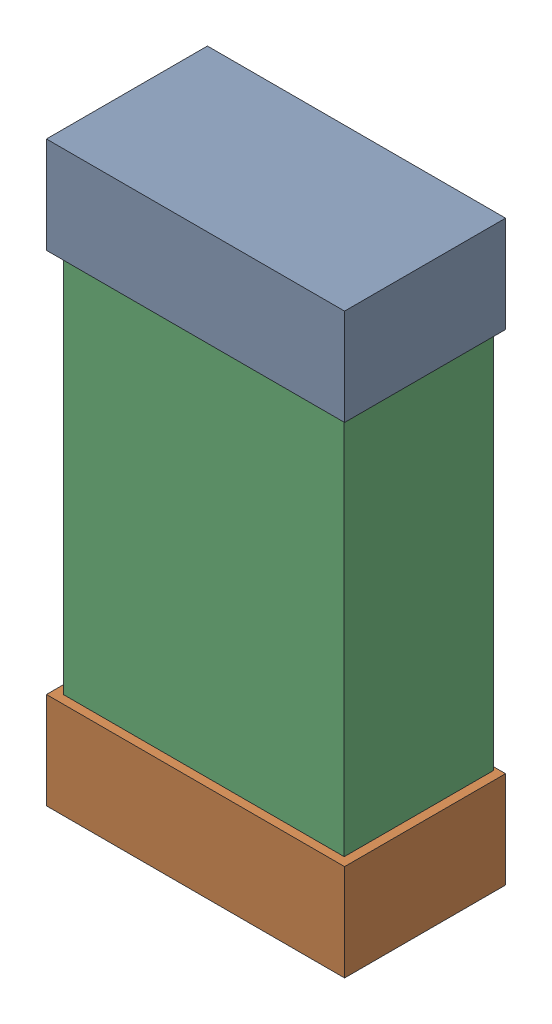
SolidWorks assembly R27, configuration Default. Lengths in mm.
Overall size (0.85 1.65 0.46).
6 component instances, 2 part files, 0 mates.
Components (placement in the parent):
- 432138512_114-1: 432138512_114 [Default] at (14.2251 20.139 -0.8715) size (0.85 0.28 0.46)
  - Extruded-1: Extruded [Default] at origin size (0.85 0.28 0.46)
- 432138512_115-1: 432138512_115 [Default] at (14.2251 18.7675 -0.8715) size (0.85 0.28 0.46)
  - Extruded-1: Extruded [Default] at origin size (0.85 0.28 0.46)
- 432124816_57-1: 432124816_57 [Default] at (14.2251 19.4533 -0.8615) size (0.8 1.5 0.42)
  - Extruded (1)-1: Extruded (1) [Default] at origin size (0.8 1.5 0.42)
